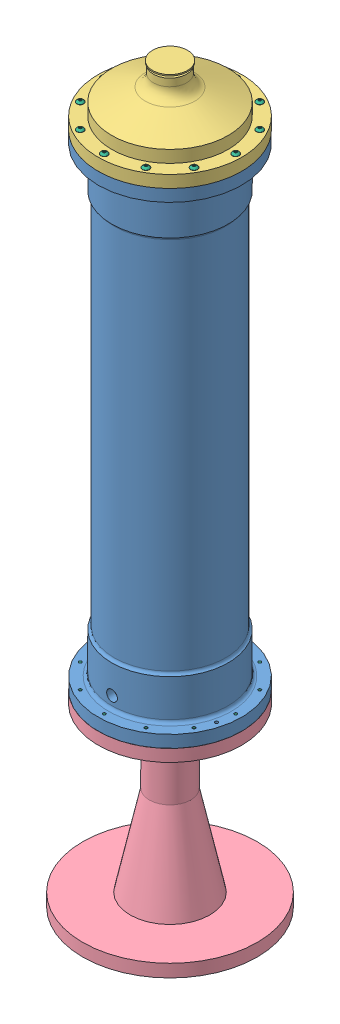
SolidWorks assembly Banshee V1 Assembly w injectioncylinder, configuration Simplify_1. Lengths in mm.
Overall size (153.97 575.88 153.97).
38 component instances, 12 part files, 30 mates.
Components (placement in the parent):
- Combustion Chamber w Insert-1: Combustion Chamber w Insert [Simplify_1] at (176.1481 58.3623 369.9746) size (112.71 381 112.71)
- Glass Insert 13 inch-1: Glass Insert 13 inch [Default] at (176.1481 108.3623 369.9746) x (0.997242 0 -0.074219) z (0.074219 0 0.997242)
- Injector Port-1: Injector Port [Simplify_1] at (176.1481 439.3623 369.9746) x (0 1 0) z (0.866025 0 0.5) size (47.36 112.71 112.71)
- Nozzle Base-1: Nozzle Base [Simplify_1] at (176.1481 58.3623 369.9746) x (0 -1 0) z (1 0 0) size (147.52 137.13 137.13)
- Throat Insert-1: Throat Insert [Default] at (176.1481 47.5673 369.9746) x (-0.397994 0 0.917388) z (0 1 0)
- 4-40 Bolt-1: 4-40 Bolt [92949A113] at (201.9608 440.1116 414.6836) x (-0.310763 0 0.950488) z (0 1 0)
- 4-40 Bolt-2: 4-40 Bolt [92949A113] at (176.1481 440.1116 421.6001) x (-0.744372 0 0.667765) z (0 1 0)
- 4-40 Bolt-3: 4-40 Bolt [92949A113] at (150.3353 440.1116 414.6836) x (-0.978528 0 0.206116) z (0 1 0)
- 4-40 Bolt-4: 4-40 Bolt [92949A113] at (131.4391 440.1116 395.7873) x (-0.950488 0 -0.310763) z (0 1 0)
- 4-40 Bolt-5: 4-40 Bolt [92949A113] at (124.5226 440.1116 369.9746) x (-0.667765 0 -0.744372) z (0 1 0)
- 4-40 Bolt-6: 4-40 Bolt [92949A113] at (131.4391 440.1116 344.1618) x (-0.206116 0 -0.978528) z (0 1 0)
- 4-40 Bolt-7: 4-40 Bolt [92949A113] at (150.3353 440.1116 325.2656) x (0.310763 0 -0.950488) z (0 1 0)
- 4-40 Bolt-8: 4-40 Bolt [92949A113] at (176.1481 440.1116 318.3491) x (0.744372 0 -0.667765) z (0 1 0)
- 4-40 Bolt-9: 4-40 Bolt [92949A113] at (201.9608 440.1116 325.2656) x (0.978528 0 -0.206116) z (0 1 0)
- 4-40 Bolt-10: 4-40 Bolt [92949A113] at (220.8571 440.1116 344.1618) x (0.950488 0 0.310763) z (0 1 0)
- 4-40 Bolt-11: 4-40 Bolt [92949A113] at (227.7736 440.1116 369.9746) x (0.667765 0 0.744372) z (0 1 0)
- 4-40 Bolt-12: 4-40 Bolt [92949A113] at (220.8571 440.1116 395.7873) x (0.206116 0 0.978528) z (0 1 0)
- 4-40 Bolt-13: 4-40 Bolt [92949A113] at (176.1481 57.613 421.6001) x (1 0 0) z (0 -1 0)
- 4-40 Bolt-14: 4-40 Bolt [92949A113] at (201.9608 57.613 414.6836) x (0.866025 0 -0.5) z (0 -1 0)
- 4-40 Bolt-15: 4-40 Bolt [92949A113] at (220.8571 57.613 395.7873) x (0.5 0 -0.866025) z (0 -1 0)
- 4-40 Bolt-16: 4-40 Bolt [92949A113] at (227.7736 57.613 369.9746) x (0 0 -1) z (0 -1 0)
- 4-40 Bolt-17: 4-40 Bolt [92949A113] at (220.8571 57.613 344.1618) x (-0.5 0 -0.866025) z (0 -1 0)
- 4-40 Bolt-18: 4-40 Bolt [92949A113] at (201.9608 57.613 325.2656) x (-0.866025 0 -0.5) z (0 -1 0)
- 4-40 Bolt-19: 4-40 Bolt [92949A113] at (176.1481 57.613 318.3491) x (-1 0 0) z (0 -1 0)
- 4-40 Bolt-20: 4-40 Bolt [92949A113] at (150.3353 57.613 325.2656) x (-0.866025 0 0.5) z (0 -1 0)
- 4-40 Bolt-21: 4-40 Bolt [92949A113] at (131.4391 57.613 344.1618) x (-0.5 0 0.866025) z (0 -1 0)
- 4-40 Bolt-22: 4-40 Bolt [92949A113] at (124.5226 57.613 369.9746) x (0 0 1) z (0 -1 0)
- 4-40 Bolt-23: 4-40 Bolt [92949A113] at (131.4391 57.613 395.7873) x (0.5 0 0.866025) z (0 -1 0)
- 4-40 Bolt-24: 4-40 Bolt [92949A113] at (150.3353 57.613 414.6836) x (0.866025 0 0.5) z (0 -1 0)
- Dowel Pin-1: Dowel Pin [90145A503] at (226.0145 439.3623 383.3362) x (0 -1 0) z (-0.75794 0 0.652324)
- Dowel Pin-2: Dowel Pin [90145A503] at (226.0145 58.3623 383.3362) x (0 1 0) z (-0.738209 0 0.674573)
- Dowel Pin-3: Dowel Pin [Simplify_1] at (126.2817 58.3623 356.6129) x (0 1 0) z (0.738209 0 -0.674573) size (9.53 4.76 4.76)
- Dowel Pin-4: Dowel Pin [Simplify_1] at (126.2817 439.3623 356.6129) x (0 -1 0) z (0.75794 0 -0.652324) size (9.53 4.76 4.76)
- Swirl Atomizer-1: Swirl Atomizer [Simplify_1] at (176.1481 442.5373 369.9746) x (0.866025 0 0.5) z (-0.5 0 0.866025) size (76.2 18.42 76.2)
- Oxidizer Plate - Copy-1: Oxidizer Plate - Copy [Default] at (176.1481 439.3623 369.9746) x (0.866025 0 0.5) z (-0.5 0 0.866025)
- Graphite Insert Top-1: Graphite Insert Top [Default] at (176.1481 413.9623 369.9746) x (0.620498 0 -0.784208) z (0.784208 0 0.620498)
- Graphite Insert Bottom-1: Graphite Insert Bottom [Default] at (176.1481 108.3623 369.9746) x (0 0 -1) z (-1 0 0)
- HTPB Fuel Grain-1: HTPB Fuel Grain [Default] at (176.1481 108.3623 369.9746) x (-0.090994 0 -0.995851) z (0.995851 0 -0.090994)
Mates (geometry in assembly coordinates):
- Concentric1: concentric aligned: cylinder of Combustion Chamber w Insert-1 through (176.1481 439.3623 369.9746) axis (0 -1 0) radius 40; cylinder of Glass Insert 13 inch-1 through (176.1481 418.5623 369.9746) axis (0 -1 0) radius 37.5
- Concentric2: concentric anti-aligned: cylinder of Combustion Chamber w Insert-1 through (176.1481 429.8373 369.9746) axis (0 1 0) radius 56.3562; cylinder of Injector Port-1 through (176.1481 439.3623 369.9746) axis (0 -1 0) radius 56.3562
- Concentric3: concentric anti-aligned: cylinder of Combustion Chamber w Insert-1 through (126.2817 439.3623 356.6129) axis (0 1 0) radius 2.3813; cylinder of Injector Port-1 through (126.2817 439.3623 356.6129) axis (0 -1 0) radius 2.3813
- Coincident2: coincident anti-aligned: plane of Combustion Chamber w Insert-1 through (176.1481 439.3623 369.9746) normal (0 1 0); plane of Injector Port-1 through (176.1481 439.3623 369.9746) normal (0 -1 0)
- Concentric4: concentric anti-aligned: cylinder of Combustion Chamber w Insert-1 through (176.1481 67.8873 369.9746) axis (0 -1 0) radius 56.3562; cylinder of Nozzle Base-1 through (176.1481 58.3623 369.9746) axis (0 1 0) radius 56.388
- Concentric5: concentric anti-aligned: cylinder of Combustion Chamber w Insert-1 through (126.2817 58.3623 356.6129) axis (0 -1 0) radius 2.3813; cylinder of Nozzle Base-1 through (126.2817 58.3623 356.6129) axis (0 1 0) radius 2.3813
- Coincident3: coincident anti-aligned: plane of Combustion Chamber w Insert-1 through (176.1481 58.3623 369.9746) normal (0 -1 0); plane of Nozzle Base-1 through (176.1481 58.3623 349.3911) normal (0 1 0)
- Concentric6: concentric aligned: cylinder of Nozzle Base-1 through (176.1481 58.3623 369.9746) axis (0 1 0) radius 14.351; cylinder of Throat Insert-1 through (176.1481 47.5673 369.9746) axis (0 1 0) radius 14.351
- Coincident4: coincident aligned: circle of Nozzle Base-1; circle of Throat Insert-1
- Concentric7: concentric anti-aligned: cylinder of Injector Port-1 through (201.9608 439.3623 414.6836) axis (0 -1 0) radius 1.4351; circle of 4-40 Bolt-1
- Coincident5: coincident anti-aligned: plane of Injector Port-1 through (153.2881 448.8873 409.5693) normal (0 1 0); plane of 4-40 Bolt-1 through (204.532 448.8873 415.5242) normal (0 -1 0)
- Concentric8: concentric anti-aligned: cylinder of Nozzle Base-1 through (176.1481 58.3623 421.6001) axis (0 1 0) radius 1.4351; circle of 4-40 Bolt-13
- Coincident6: coincident anti-aligned: plane of Nozzle Base-1 through (176.1481 48.8373 313.5866) normal (0 -1 0); plane of 4-40 Bolt-13 through (176.1481 48.8373 424.3052) normal (0 1 0)
- Concentric9: concentric anti-aligned: cylinder of Combustion Chamber w Insert-1 through (226.0145 439.3623 383.3362) axis (0 1 0) radius 2.3813; cylinder of Dowel Pin-1 through (226.0145 444.1248 383.3362) axis (0 -1 0) radius 2.3813
- Coincident8: coincident anti-aligned: plane of Combustion Chamber w Insert-1 through (227.2051 434.5998 383.3362) normal (0 1 0); plane of Dowel Pin-1 through (226.0145 434.5998 383.3362) normal (0 -1 0)
- Concentric10: concentric anti-aligned: cylinder of Combustion Chamber w Insert-1 through (226.0145 58.3623 383.3362) axis (0 -1 0) radius 2.3813; cylinder of Dowel Pin-2 through (226.0145 53.5998 383.3362) axis (0 1 0) radius 2.3813
- Coincident9: coincident anti-aligned: plane of Combustion Chamber w Insert-1 through (227.2051 63.1248 383.3362) normal (0 -1 0); plane of Dowel Pin-2 through (226.0145 63.1248 383.3362) normal (0 1 0)
- Concentric11: concentric aligned: cylinder of Injector Port-1 through (176.1481 443.1723 369.9746) axis (0 -1 0) radius 38.1; cylinder of Swirl Atomizer-1 through (176.1481 445.7123 369.9746) axis (0 -1 0) radius 38.1
- Coincident10: coincident anti-aligned: plane of Injector Port-1 through (176.1481 445.7123 369.9746) normal (0 -1 0); plane of Swirl Atomizer-1 through (176.1481 445.7123 369.9746) normal (0 1 0)
- Concentric12: concentric aligned: cylinder of Injector Port-1 through (147.277 445.7123 353.3058) axis (0 -1 0) radius 1.1303; cylinder of Swirl Atomizer-1 through (147.277 442.5373 353.3058) axis (0 -1 0) radius 1.1303
- Concentric13: concentric aligned: cylinder of Injector Port-1 through (176.1481 443.1723 369.9746) axis (0 -1 0) radius 38.1; cylinder of Oxidizer Plate - Copy-1 through (176.1481 442.5373 369.9746) axis (0 -1 0) radius 38.1
- Coincident11: coincident anti-aligned: plane of Swirl Atomizer-1 through (176.1481 442.5373 369.9746) normal (0 -1 0); plane of Oxidizer Plate - Copy-1 through (176.1481 442.5373 369.9746) normal (0 1 0)
- Concentric14: concentric aligned: cylinder of Swirl Atomizer-1 through (147.277 442.5373 353.3058) axis (0 -1 0) radius 1.1303; cylinder of Oxidizer Plate - Copy-1 through (147.277 439.3623 353.3058) axis (0 -1 0) radius 1.1303
- Concentric15: concentric anti-aligned: cylinder of Combustion Chamber w Insert-1 through (176.1481 398.0873 369.9746) axis (0 1 0) radius 45.72; cylinder of Graphite Insert Top-1 through (176.1481 439.3623 369.9746) axis (0 -1 0) radius 40
- Coincident12: coincident anti-aligned: plane of Injector Port-1 through (176.1481 439.3623 369.9746) normal (0 -1 0); plane of Graphite Insert Top-1 through (176.1481 439.3623 369.9746) normal (0 1 0)
- Coincident13: coincident anti-aligned: plane of Nozzle Base-1 through (176.1481 58.3623 349.3911) normal (0 1 0); plane of Graphite Insert Bottom-1 through (176.1481 58.3623 369.9746) normal (0 -1 0)
- Concentric18: concentric aligned: cylinder of Combustion Chamber w Insert-1 through (176.1481 439.3623 369.9746) axis (0 -1 0) radius 43.815; cylinder of HTPB Fuel Grain-1 through (176.1481 418.5623 369.9746) axis (0 -1 0) radius 35
- Coincident14: coincident anti-aligned: plane of Graphite Insert Bottom-1 through (176.1481 108.3623 369.9746) normal (0 1 0); plane of HTPB Fuel Grain-1 through (176.1481 108.3623 369.9746) normal (0 -1 0)
- Concentric19: concentric anti-aligned: cylinder of Combustion Chamber w Insert-1 through (176.1481 439.3623 369.9746) axis (0 -1 0) radius 40; cylinder of Graphite Insert Bottom-1 through (176.1481 58.3623 369.9746) axis (0 1 0) radius 40
- Coincident15: coincident anti-aligned: plane of Glass Insert 13 inch-1 through (176.1481 108.3623 369.9746) normal (0 -1 0); plane of Graphite Insert Bottom-1 through (176.1481 108.3623 369.9746) normal (0 1 0)
